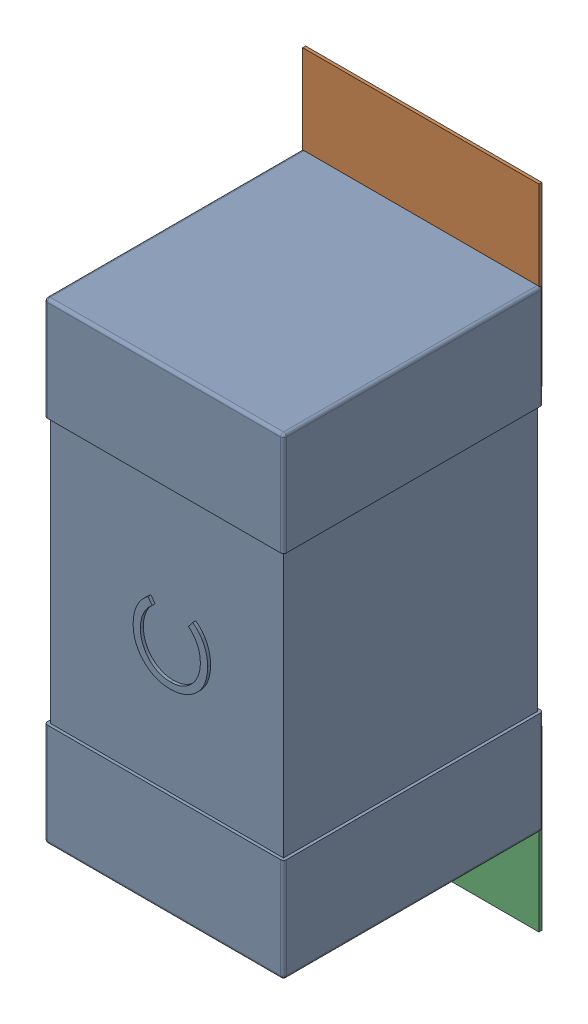
SolidWorks assembly C97, configuration Défaut. Lengths in mm.
Overall size (0.81 2.19 0.88).
5 component instances, 2 part files, 0 mates.
Components (placement in the parent):
- 0603_C-1: 0603_C [Défaut] at (45.466 -36.8228 0) x (0 1 0) z (0 0 1) size (1.6 0.81 0.88)
- 8260087904-1: 8260087904 [Défaut] at (45.466 -35.5728 0) size (0.8 0.6 0.01)
  - Extruded_1211-1: Extruded_1211 [Défaut] at origin size (0.8 0.6 0.01)
- 8260087904-2: 8260087904 [Défaut] at (45.466 -37.1677 0) size (0.8 0.6 0.01)
  - Extruded_1211-1: Extruded_1211 [Défaut] at origin size (0.8 0.6 0.01)
